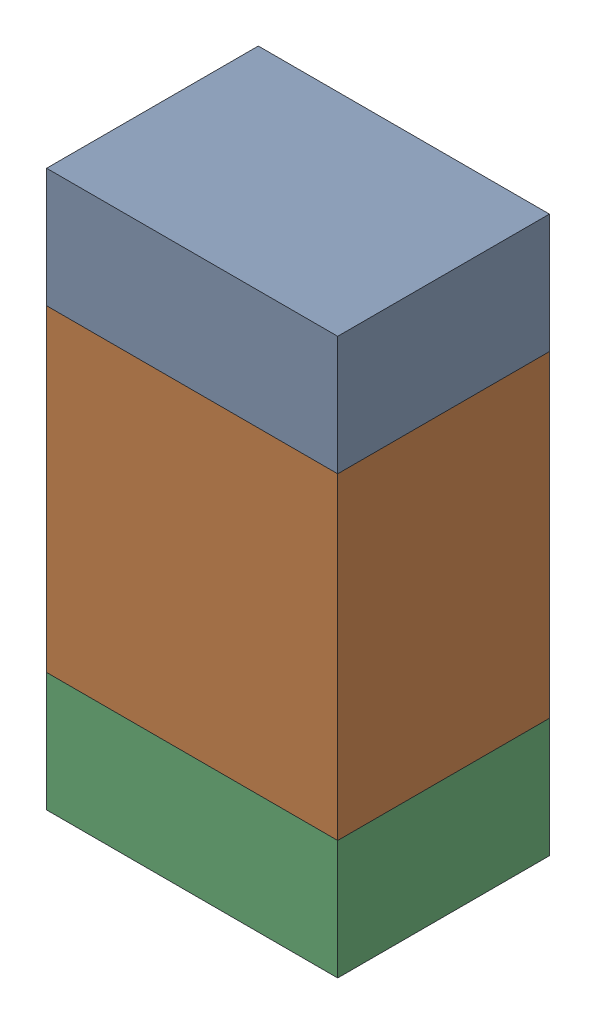
SolidWorks assembly R107_2PCB, configuration Default. Lengths in mm.
Overall size (0.55 1.05 0.4).
6 component instances, 2 part files, 0 mates.
Components (placement in the parent):
- 846483288-1: 846483288 [Default] at (115.1001 100.0124 0) size (0.55 0.22 0.4)
  - Extruded_12-1: Extruded_12 [Default] at origin size (0.55 0.22 0.4)
- 846483424-1: 846483424 [Default] at (115.1001 99.5999 0) size (0.55 0.6 0.4)
  - Extruded_13-1: Extruded_13 [Default] at origin size (0.55 0.6 0.4)
- 846483288-2: 846483288 [Default] at (115.1001 99.1874 0) size (0.55 0.22 0.4)
  - Extruded_12-1: Extruded_12 [Default] at origin size (0.55 0.22 0.4)
